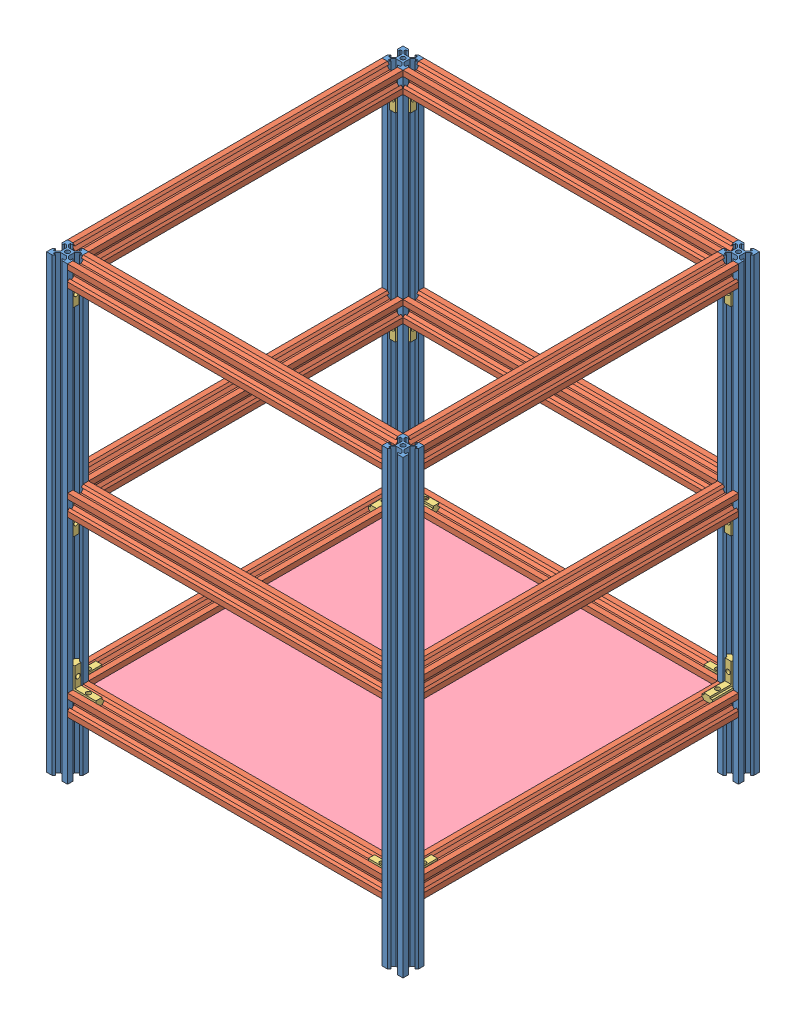
SolidWorks assembly box300, configuration 默认. Lengths in mm.
Overall size (340 430 340).
44 component instances, 4 part files, 19 mates.
Components (placement in the parent):
- 2020lv_430-1: 2020lv_430 [默认] at (-30.9213 -257.9463 430) size (20 430 20)
- layer30-1: layer30 [默认] at (-76.4644 107.4521 199.2884) x (-1 0 0) z (0 -1 0) size (340 340 42.68)
  - 2020lv_300-1: 2020lv_300 [默认] at (-45.5431 -220.7116 300) size (20 300 20)
  - 2020lv_300-2: 2020lv_300 [默认] at (-55.5431 -230.7116 300) x (0 1 0) z (0 0 1) size (20 300 20)
  - 2020lv_300-3: 2020lv_300 [默认] at (-55.5431 89.2884 300) x (0 1 0) z (0 0 1) size (20 300 20)
  - 2020lv_300-4: 2020lv_300 [默认] at (-365.5431 -220.7116 300) size (20 300 20)
  - 2020jiaocao-1: 2020jiaocao [默认] at (-47.4431 79.2884 293.1) x (0 0 -1) z (-1 0 0) size (25 26 10)
  - 2020jiaocao-2: 2020jiaocao [默认] at (-55.5431 91.1884 293.1) x (0 0 -1) z (0 1 0) size (25 26 10)
  - 2020jiaocao-3: 2020jiaocao [默认] at (-355.5431 89.3884 293) x (0 0 -1) z (0 -1 0) size (25 26 10)
  - 2020jiaocao-4: 2020jiaocao [默认] at (-365.6431 79.2884 289.3206) x (0 0 -1) z (-1 0 0) size (25 26 10)
  - 2020jiaocao-5: 2020jiaocao [默认] at (-365.4431 -220.7116 293) x (0 0 -1) z (1 0 0) size (25 26 10)
  - 2020jiaocao-6: 2020jiaocao [默认] at (-355.5431 -230.8116 293) x (0 0 -1) z (0 -1 0) size (25 26 10)
  - 2020jiaocao-7: 2020jiaocao [默认] at (-55.5431 -230.8116 293) x (0 0 -1) z (0 1 0) size (25 26 10)
  - 2020jiaocao-8: 2020jiaocao [默认] at (-45.4431 -220.7116 293) x (0 0 -1) z (1 0 0) size (25 26 10)
- 2020lv_430-2: 2020lv_430 [默认] at (289.0787 -257.9463 430) size (20 430 20)
- layer30-2: layer30 [默认] at (-76.4644 -137.9463 340.7116) x (-1 0 0) z (0 1 0) size (340 340 42.68)
  - 2020lv_300-1: 2020lv_300 [默认] at (-45.5431 -220.7116 300) size (20 300 20)
  - 2020lv_300-2: 2020lv_300 [默认] at (-55.5431 -230.7116 300) x (0 1 0) z (0 0 1) size (20 300 20)
  - 2020lv_300-3: 2020lv_300 [默认] at (-55.5431 89.2884 300) x (0 1 0) z (0 0 1) size (20 300 20)
  - 2020lv_300-4: 2020lv_300 [默认] at (-365.5431 -220.7116 300) size (20 300 20)
  - 2020jiaocao-1: 2020jiaocao [默认] at (-47.4431 79.2884 293.1) x (0 0 -1) z (-1 0 0) size (25 26 10)
  - 2020jiaocao-2: 2020jiaocao [默认] at (-55.5431 91.1884 293.1) x (0 0 -1) z (0 1 0) size (25 26 10)
  - 2020jiaocao-3: 2020jiaocao [默认] at (-355.5431 89.3884 293) x (0 0 -1) z (0 -1 0) size (25 26 10)
  - 2020jiaocao-4: 2020jiaocao [默认] at (-365.6431 79.2884 289.3206) x (0 0 -1) z (-1 0 0) size (25 26 10)
  - 2020jiaocao-5: 2020jiaocao [默认] at (-365.4431 -220.7116 293) x (0 0 -1) z (1 0 0) size (25 26 10)
  - 2020jiaocao-6: 2020jiaocao [默认] at (-355.5431 -230.8116 293) x (0 0 -1) z (0 -1 0) size (25 26 10)
  - 2020jiaocao-7: 2020jiaocao [默认] at (-55.5431 -230.8116 293) x (0 0 -1) z (0 1 0) size (25 26 10)
  - 2020jiaocao-8: 2020jiaocao [默认] at (-45.4431 -220.7116 293) x (0 0 -1) z (1 0 0) size (25 26 10)
- 2020lv_430-3: 2020lv_430 [默认] at (289.0787 -257.9463 110) size (20 430 20)
- 2020lv_430-4: 2020lv_430 [默认] at (-30.9213 -257.9463 110) size (20 430 20)
- layer30-3: layer30 [默认] at (-76.4644 -327.3417 340.7116) x (-1 0 0) z (0 1 0) size (340 340 42.68)
  - 2020lv_300-1: 2020lv_300 [默认] at (-45.5431 -220.7116 300) size (20 300 20)
  - 2020lv_300-2: 2020lv_300 [默认] at (-55.5431 -230.7116 300) x (0 1 0) z (0 0 1) size (20 300 20)
  - 2020lv_300-3: 2020lv_300 [默认] at (-55.5431 89.2884 300) x (0 1 0) z (0 0 1) size (20 300 20)
  - 2020lv_300-4: 2020lv_300 [默认] at (-365.5431 -220.7116 300) size (20 300 20)
  - 2020jiaocao-1: 2020jiaocao [默认] at (-47.4431 79.2884 293.1) x (0 0 -1) z (-1 0 0) size (25 26 10)
  - 2020jiaocao-2: 2020jiaocao [默认] at (-55.5431 91.1884 293.1) x (0 0 -1) z (0 1 0) size (25 26 10)
  - 2020jiaocao-3: 2020jiaocao [默认] at (-355.5431 89.3884 293) x (0 0 -1) z (0 -1 0) size (25 26 10)
  - 2020jiaocao-4: 2020jiaocao [默认] at (-365.6431 79.2884 289.3206) x (0 0 -1) z (-1 0 0) size (25 26 10)
  - 2020jiaocao-5: 2020jiaocao [默认] at (-365.4431 -220.7116 293) x (0 0 -1) z (1 0 0) size (25 26 10)
  - 2020jiaocao-6: 2020jiaocao [默认] at (-355.5431 -230.8116 293) x (0 0 -1) z (0 -1 0) size (25 26 10)
  - 2020jiaocao-7: 2020jiaocao [默认] at (-55.5431 -230.8116 293) x (0 0 -1) z (0 1 0) size (25 26 10)
  - 2020jiaocao-8: 2020jiaocao [默认] at (-45.4431 -220.7116 293) x (0 0 -1) z (1 0 0) size (25 26 10)
- ban-1: ban [默认] at (127.9787 -193.4479 271.1) size (310 4 310)
Mates (geometry in assembly coordinates):
- 重合1: coincident aligned: plane of 2020lv_430-1 through (-40.9213 172.0537 440) normal (0 0 1); plane of layer30-1/2020lv_300-2 through (279.0787 -202.5479 440) normal (0 0 1)
- 重合2: coincident anti-aligned: plane of 2020lv_430-1 through (-20.9213 172.0537 440) normal (1 0 0); plane of layer30-1/2020lv_300-2 through (-20.9213 -192.5479 430) normal (-1 0 0)
- 重合3: coincident aligned: plane of 2020lv_430-1 through (-30.9213 172.0537 430) normal (0 1 0); plane of 2020lv_430-2 through (289.0787 172.0537 430) normal (0 1 0)
- 重合4: coincident anti-aligned: plane of layer30-1/2020lv_300-4 through (289.0787 -192.5479 420) normal (0 0 1); plane of 2020lv_430-2 through (299.0787 172.0537 420) normal (0 0 -1)
- 重合5: coincident aligned: plane of layer30-1/2020lv_300-4 through (299.0787 -182.5479 120) normal (1 0 0); plane of 2020lv_430-2 through (299.0787 172.0537 420) normal (1 0 0)
- 重合6: coincident aligned: plane of 2020lv_430-1 through (-30.9213 172.0537 430) normal (0 1 0); plane of layer30-2/2020lv_300-2 through (279.0787 172.0537 120) normal (0 1 0)
- 重合7: coincident anti-aligned: plane of 2020lv_430-1 through (-20.9213 172.0537 420) normal (0 0 -1); plane of layer30-2/2020lv_300-1 through (-30.9213 162.0537 420) normal (0 0 1)
- 重合8: coincident anti-aligned: plane of 2020lv_430-1 through (-20.9213 172.0537 420) normal (1 0 0); plane of layer30-2/2020lv_300-3 through (-20.9213 162.0537 430) normal (-1 0 0)
- 重合9: coincident aligned: plane of layer30-1/2020lv_300-4 through (299.0787 -202.5479 120) normal (1 0 0); plane of 2020lv_430-3 through (299.0787 172.0537 120) normal (1 0 0)
- 重合10: coincident anti-aligned: plane of layer30-1/2020lv_300-4 through (289.0787 -192.5479 120) normal (0 0 -1); plane of 2020lv_430-3 through (299.0787 172.0537 120) normal (0 0 1)
- 重合11: coincident aligned: plane of layer30-2/2020lv_300-4 through (279.0787 172.0537 420) normal (0 1 0); plane of 2020lv_430-3 through (289.0787 172.0537 110) normal (0 1 0)
- 重合12: coincident aligned: plane of layer30-1/2020lv_300-3 through (279.0787 -182.5479 100) normal (0 0 -1); plane of 2020lv_430-4 through (-40.9213 172.0537 100) normal (0 0 -1)
- 重合13: coincident anti-aligned: plane of layer30-1/2020lv_300-3 through (-20.9213 -192.5479 110) normal (-1 0 0); plane of 2020lv_430-4 through (-20.9213 172.0537 100) normal (1 0 0)
- 重合14: coincident aligned: plane of layer30-2/2020lv_300-1 through (-20.9213 172.0537 420) normal (0 1 0); plane of 2020lv_430-4 through (-30.9213 172.0537 110) normal (0 1 0)
- 重合15: coincident aligned: plane of 2020lv_430-2 through (299.0787 172.0537 440) normal (0 0 1); plane of layer30-3/2020lv_300-3 through (279.0787 -37.3417 440) normal (0 0 1)
- 重合16: coincident anti-aligned: plane of 2020lv_430-2 through (279.0787 172.0537 440) normal (-1 0 0); plane of layer30-3/2020lv_300-3 through (279.0787 -27.3417 430) normal (1 0 0)
- 重合18: coincident: line of layer30-1/2020lv_300-3 through (279.0787 -189.4479 118.2) axis (-1 0 0); plane of ban-1 through (127.9787 -189.4479 271.1) normal (0 1 0)
- 重合19: coincident anti-aligned: plane of layer30-1/2020lv_300-2 through (279.0787 -189.7085 426.1) normal (0 0 -1); plane of ban-1 through (-27.0213 -189.4479 426.1) normal (0 0 1)
- 重合20: coincident anti-aligned: plane of layer30-1/2020lv_300-1 through (-27.0213 -189.7085 120) normal (1 0 0); plane of ban-1 through (-27.0213 -189.4479 426.1) normal (-1 0 0)
